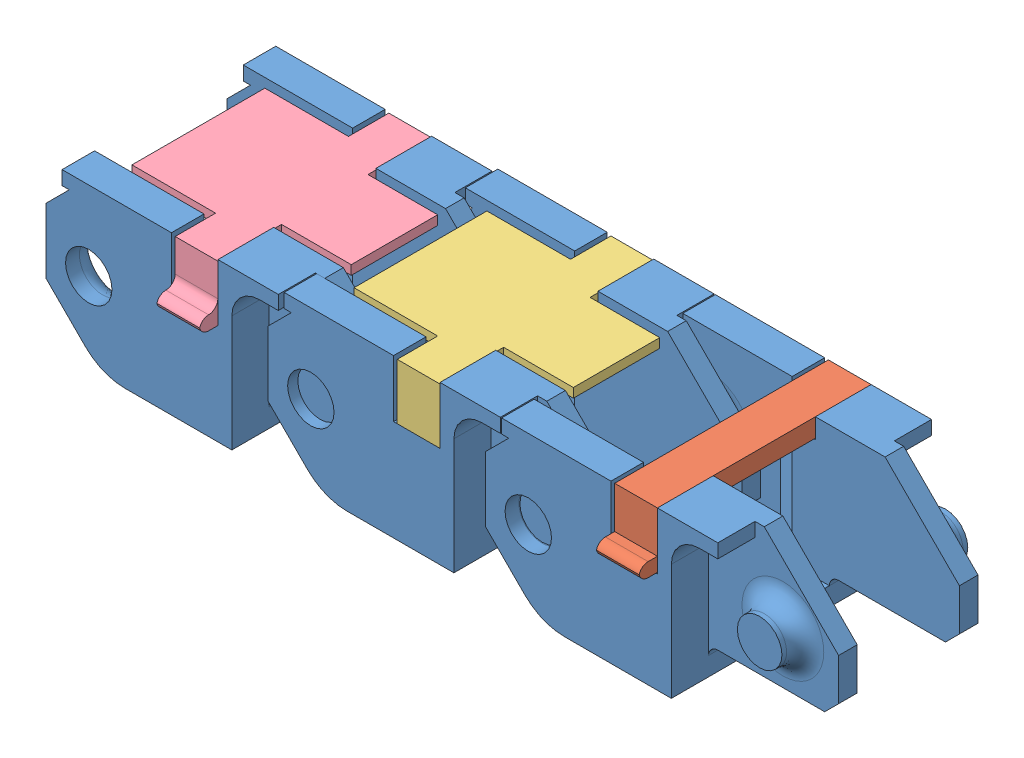
SolidWorks assembly Ensamblaje Eslabon 15, configuration Predeterminado. Lengths in mm.
Overall size (80.8 17 27.44).
6 component instances, 4 part files, 15 mates.
Components (placement in the parent):
- Eslabon 15-1: Eslabon 15 [Predeterminado] at (-29.411 -6.9992 30.5) size (34 17 23)
- Cierre 15-1: Cierre 15 [Predeterminado] at (-10.911 10.0008 49.5) x (-1 0 0) z (0 0 1) size (4.6 6 24.97)
- Eslabon 15-2: Eslabon 15 [Predeterminado] at (-52.811 -6.9992 30.5) size (34 17 23)
- Eslabon 15-3: Eslabon 15 [Predeterminado] at (-76.211 -6.9992 31) size (34 17 23)
- Cierre 15 Tapa R-1: Cierre 15 Tapa R [Predeterminado] at (-38.911 9.8508 26.5) x (1 0 0) z (0 0 -1) size (21.1 6 24.97)
- Cierre 15 Tapa L-2: Cierre 15 Tapa L [Predeterminado] at (-57.711 9.8508 50) x (-1 0 0) z (0 0 1) size (21.1 6 24.97)
Mates (geometry in assembly coordinates):
- Coincidente1: coincident aligned: plane of Eslabon 15-1 through (-29.411 10.0008 30.5) normal (0 1 0); plane of Cierre 15-1 through (-10.911 10.0008 49.5) normal (0 1 0)
- Coincidente2: coincident anti-aligned: plane of Eslabon 15-1 through (-10.911 7.8508 26.5) normal (-1 0 0); plane of Cierre 15-1 through (-10.911 8.0008 49.5) normal (1 0 0)
- Coincidente3: coincident aligned: plane of Eslabon 15-1 through (-29.411 -4.9992 49.5) normal (0 0 1); plane of Cierre 15-1 through (-10.911 8.0008 49.5) normal (0 0 1)
- Distancia1: distance = 0.5 mm anti-aligned: plane of Eslabon 15-2 through (-18.811 -4.9992 30.5) normal (0 0 -1); plane of Eslabon 15-1 through (-15.911 -18.5084 30) normal (0 0 1)
- Concéntrica1: concentric aligned: circle of Eslabon 15-1; circle of Eslabon 15-2
- Concéntrica2: concentric aligned: circle of Eslabon 15-2; circle of Eslabon 15-3
- Coincidente4: coincident anti-aligned: plane of Eslabon 15-2 through (-39.311 -18.5084 46) normal (0 0 -1); plane of Eslabon 15-3 through (-56.211 -4.9992 46) normal (0 0 1)
- Paralelo1: parallel anti-aligned: plane of Eslabon 15-1 through (-27.681 10.0008 32.7208) normal (-1 0 0); plane of Eslabon 15-2 through (-27.811 -6.9992 30.5) normal (1 0 0)
- Paralelo2: parallel anti-aligned: plane of Eslabon 15-2 through (-51.081 10.0008 32.7208) normal (-1 0 0); plane of Eslabon 15-3 through (-51.211 -6.9992 31) normal (1 0 0)
- Coincidente8: coincident anti-aligned: plane of Eslabon 15-2 through (-52.811 3.8508 30.5) normal (0 1 0); plane of Cierre 15 Tapa R-1 through (-38.911 3.8508 26.5) normal (0 -1 0)
- Coincidente9: coincident anti-aligned: plane of Eslabon 15-2 through (-34.311 7.8508 26.5) normal (-1 0 0); plane of Cierre 15 Tapa R-1 through (-34.311 7.8508 26.5) normal (1 0 0)
- Coincidente10: coincident anti-aligned: plane of Eslabon 15-2 through (-52.811 -6.9992 29.7) normal (0 0 -1); plane of Cierre 15 Tapa R-1 through (-38.911 9.8508 29.7) normal (0 0 1)
- Coincidente11: coincident anti-aligned: plane of Eslabon 15-3 through (-57.711 7.8508 27) normal (-1 0 0); plane of Cierre 15 Tapa L-2 through (-57.711 7.8508 50) normal (1 0 0)
- Coincidente12: coincident anti-aligned: plane of Eslabon 15-3 through (-76.211 3.8508 31) normal (0 1 0); plane of Cierre 15 Tapa L-2 through (-57.711 3.8508 50) normal (0 -1 0)
- Coincidente13: coincident anti-aligned: plane of Eslabon 15-3 through (-76.211 -6.9992 46.8) normal (0 0 1); plane of Cierre 15 Tapa L-2 through (-57.711 9.8508 46.8) normal (0 0 -1)
